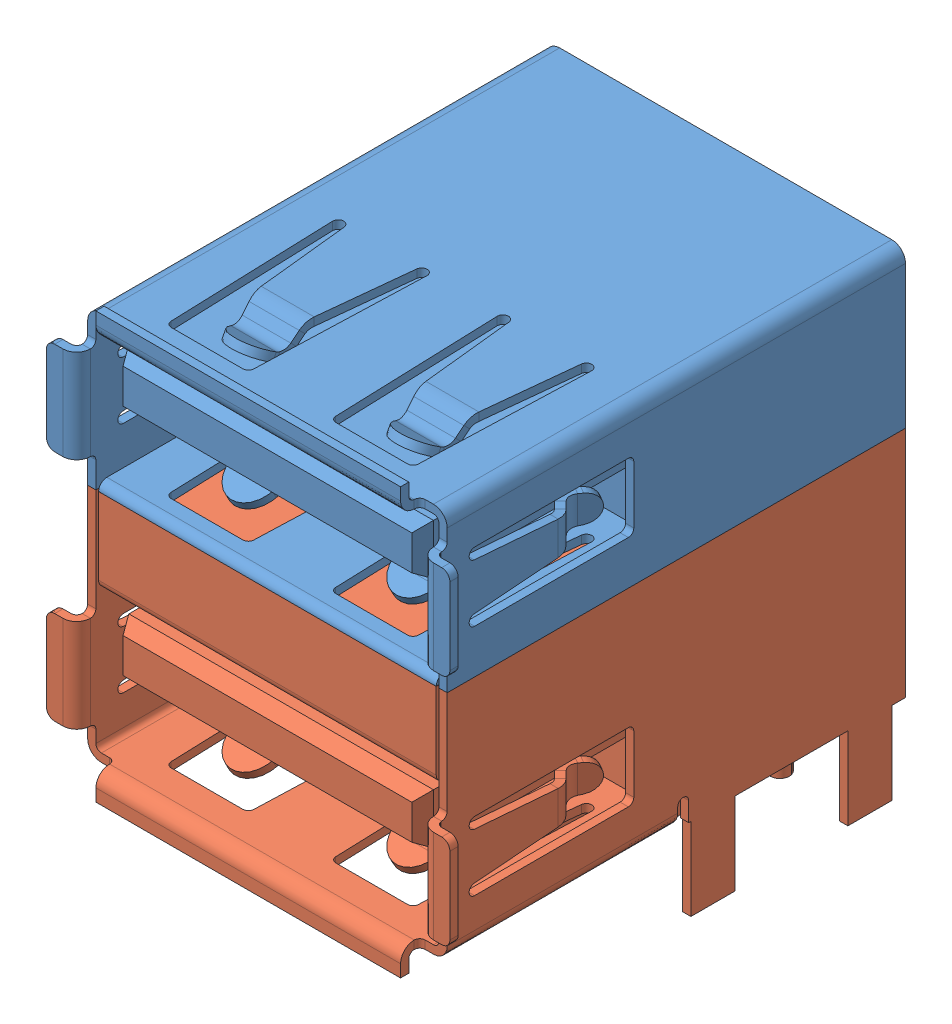
SolidWorks assembly USB-Buchse, configuration Valor predeterminado. Lengths in mm.
Overall size (14.7 17.85 17.4).
2 component instances, 2 part files, 2 mates.
Components (placement in the parent):
- USB-Buchse-Upper-1: USB-Buchse-Upper [По умолчанию] at (-114.6616 -10.9375 -4.85) x (0 0 1) z (-1 0 0) size (17.4 6.35 14.7)
- USB-Buchse-Lower-1: USB-Buchse-Lower [По умолчанию] at (-114.6616 -19.4375 -4.85) x (0 0 1) z (-1 0 0) size (17.4 11.5 14.7)
Mates (geometry in assembly coordinates):
- Coincidente5: coincident aligned: plane of USB-Buchse-Upper-1 through (-108.6116 -5.1375 -8.55) normal (0 0 -1); plane of USB-Buchse-Lower-1 through (-108.6116 -13.6375 -8.55) normal (0 0 -1)
- Coincidente6: coincident aligned: plane of USB-Buchse-Upper-1 through (-121.2116 -10.3375 -8.55) normal (-1 0 0); plane of USB-Buchse-Lower-1 through (-121.2116 -18.8375 -8.55) normal (-1 0 0)
